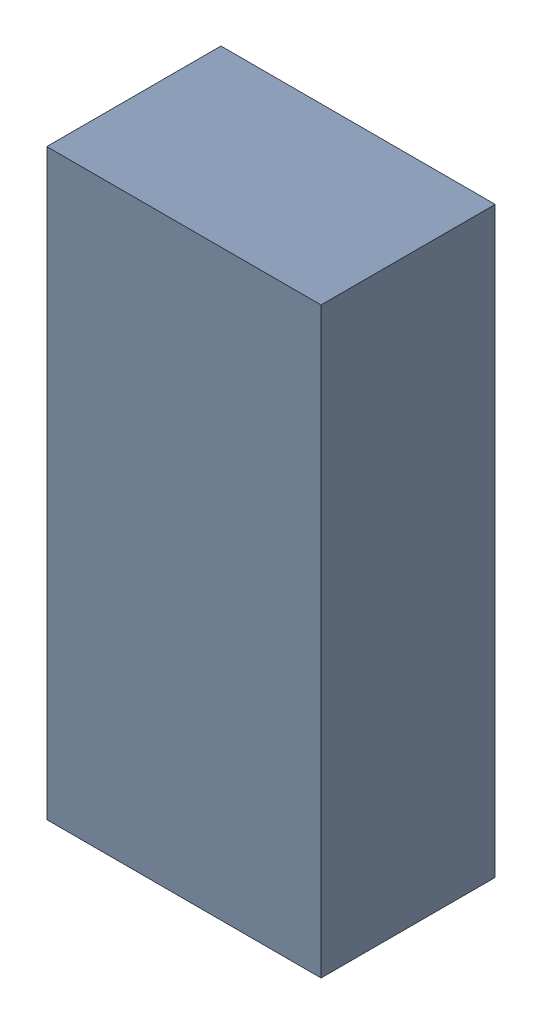
SolidWorks assembly 6327399040, configuration Default. Lengths in mm.
Overall size (0.4 0.85 0.25).
2 component instances, 1 part files, 0 mates.
Components (placement in the parent):
- 6701982208-1:  [Default] at (27.7 14.8 0) (suppressed, hidden)
- Extruded-7-1: Extruded-7 [Default] at origin size (0.4 0.85 0.25)
